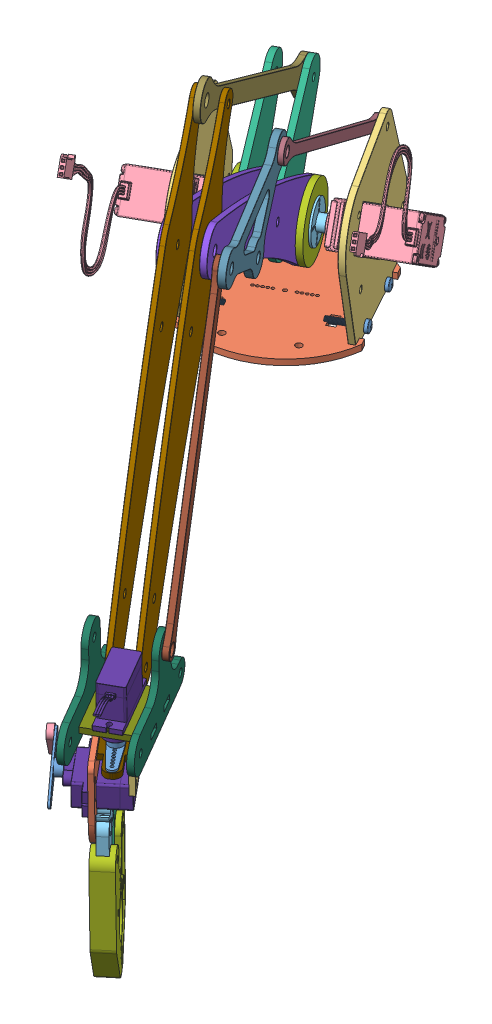
SolidWorks assembly Assem Arms2, configuration Default. Lengths in mm.
Overall size (226.25 313.58 319.53).
40 component instances, 25 part files, 102 mates.
Components (placement in the parent):
- pan head cross rece0ss screw_iso-20: pan head cross rece0ss screw_iso [ISO 7045 - M3 x 16 - Z - 16S] at (40.1963 16.3953 -44.7782) x (-0.87225 0 0.489061) z (-0.265849 -0.839351 -0.474146) size (18.35 5.6 5.6)
- pan head cross rece0ss screw_iso-22: pan head cross rece0ss screw_iso [ISO 7045 - M3 x 16 - Z - 16S] at (54.3761 16.9884 -19.4883) x (-0.87225 0 0.489061) z (0.426844 0.488109 0.761284) size (18.35 5.6 5.6)
- pan head cross rece0ss screw_iso-23: pan head cross rece0ss screw_iso [ISO 7045 - M3 x 16 - Z - 16S] at (-25.8377 16.3953 -7.7537) x (0.87225 0 -0.489061) z (0.489061 0 0.87225) size (18.35 5.6 5.6)
- pan head cross rece0ss screw_iso-24: pan head cross rece0ss screw_iso [ISO 7045 - M3 x 16 - Z - 16S] at (-11.6579 16.9884 17.5363) x (0.87225 0 -0.489061) z (0.489061 0 0.87225) size (18.35 5.6 5.6)
- Part9-1: Part9 [Default] at (14.258 13.6925 -13.5443) x (0.488959 0.020451 0.872067) z (-0.87225 0 0.489061) size (92 3 75)
- Part1-1: Part1 [Default] at (42.6761 6.6939 -29.314) x (-0.488959 -0.020451 -0.872067) z (0.87225 0 -0.489061) size (84.94 80.79 3)
- Part1-2: Part1 [Default] at (-16.5544 6.6939 3.8959) x (-0.488959 -0.020451 -0.872067) z (0.87225 0 -0.489061) size (84.94 80.79 3)
- Servo Futaba S3003.stp-1: Servo Futaba S3003.stp [Default] at (-33.8607 55.5272 21.081) x (-0.288648 0.80725 -0.51481) z (0.87225 0 -0.489061) size (44.37 151.18 42.35)
- Servo Futaba S3003.stp-2: Servo Futaba S3003.stp [Default] at (68.9822 55.5272 -36.5819) x (0.288648 -0.80725 0.51481) z (-0.87225 0 0.489061) size (44.37 151.18 42.35)
- SERVO MOTOR Leaf-2: SERVO MOTOR Leaf [Default] at (7.5067 61.4293 7.1415) x (-0.341934 -0.71496 -0.609846) z (-0.349659 0.699165 -0.623624) size (20 5 20)
- Part8-2: Part8 [Default] at (22.7419 116.7338 28.1796) x (-0.349659 0.699165 -0.623624) z (-0.87225 0 0.489061) size (80.5 35 3)
- Part8-3: Part8 [Default] at (35.4815 116.7338 21.0367) x (-0.349659 0.699165 -0.623624) z (-0.87225 0 0.489061) size (80.5 35 3)
- Waasher-3: Waasher [Default] at (10.1235 61.4293 5.6744) x (0.349659 -0.699165 0.623624) z (-0.87225 0 0.489061) size (35 35 3)
- Waasher-4: Waasher [Default] at (32.8939 61.4293 -7.0928) x (0.115909 -0.971509 0.206726) z (0.87225 0 -0.489061) size (35 35 3)
- Part2-3: Part2 [Default] at (6.2842 25.132 -48.4176) x (0.144187 -0.955551 0.257161) z (-0.87225 0 0.489061) size (60.81 172.93 3)
- Part2-4: Part2 [Default] at (-8.5441 25.132 -40.1035) x (0.144187 -0.955551 0.257161) z (-0.87225 0 0.489061) size (60.81 172.93 3)
- Part5-3: Part5 [Default] at (4.7495 30.3786 -51.1548) x (-0.343534 0.711748 -0.612699) z (0.87225 0 -0.489061) size (224.03 63.02 2.5)
- Part5-4: Part5 [Default] at (-5.2814 30.3786 -45.5306) x (-0.343534 0.711748 -0.612699) z (0.87225 0 -0.489061) size (224.03 63.02 2.5)
- SERVO MOTOR Leaf-3: SERVO MOTOR Leaf [Default] at (35.5107 61.4293 -8.56) x (-0.475127 -0.237003 -0.847398) z (0.115909 -0.971509 0.206726) size (20 5 20)
- Part22-1: Part22 [Default] at (7.5987 61.4293 7.09) x (-0.352996 -0.692118 -0.629576) z (0.338488 -0.721784 0.6037) size (8.5 32 8.5)
- part 6-2: part 6 [Default] at (11.9236 85.2607 -71.8932) x (-0.299121 0.79115 -0.533488) z (0.87225 0 -0.489061) size (153.11 32.4 3)
- Part4-2: Part4 [Default] at (-30.3251 112.5374 -90.1964) x (0.161206 -0.944113 0.287514) z (-0.87225 0 0.489061) size (50.31 174.7 3)
- Part 3-4: Part 3 [Default] at (-7.5406 76.9662 -113.7645) x (0.148401 -0.95285 0.264676) z (-0.87225 0 0.489061) size (42.48 154.39 2.5)
- Part7-2: Part7 [Default] at (122.5992 -71.5202 125.4988) x (0.48636 -0.104953 0.867432) z (-0.87225 0 0.489061) size (84.81 40.3 3.5)
- GPart 6-1: GPart 6 [Default] at (158.21 -6.5964 198.2127) x (0.488552 -0.045613 0.871342) z (-0.87225 0 0.489061) size (70 41 3)
- GPart 6-2: GPart 6 [Default] at (134.3104 -6.5964 211.613) x (0.488552 -0.045613 0.871342) z (-0.87225 0 0.489061) size (70 41 3)
- GPart 7-1: GPart 7 [Default] at (146.0278 -0.6255 205.9296) x (0.488552 -0.045613 0.871342) z (0.022308 0.998959 0.039786) size (31 29 3)
- SERVO MOTOR Leaf-4: SERVO MOTOR Leaf [Default] at (14.258 13.6925 -13.5443) x (0.489204 0.020451 0.87193) z (0.872112 -0.000006 -0.489306) size (20 5 20)
- Servo Motor-1: Servo Motor [Default] at (146.4851 19.8532 206.7452) x (0.488552 -0.045613 0.871342) z (0.87225 0 -0.489061) size (46.97 30.5 12)
- GPart 8-1: GPart 8 [Default] at (148.4136 -14.3623 210.1849) x (0.633536 -0.044911 0.772409) z (0.022308 0.998959 0.039786) size (35 18 3)
- SERVO MOTOR Leaf Straight-1: SERVO MOTOR Leaf Straight [Default] at (148.4471 -12.8639 210.2446) x (0.773392 0.007975 -0.633878) z (0.633536 -0.044911 0.772409) size (7.33 5 34.5)
- GPart 4-1: GPart 4 [Default] at (141.1343 -29.4196 215.3123) x (0.633536 -0.044911 0.772409) z (0.773392 0.007975 -0.633878) size (35 45 2.5)
- GPart 5-1: GPart 5 [Default] at (155.0554 -29.276 203.9025) x (-0.633536 0.044911 -0.772409) z (-0.773392 -0.007975 0.633878) size (35 13 2.5)
- Servo Motor-2: Servo Motor [Default] at (153.8953 -29.288 204.8533) x (-0.633536 0.044911 -0.772409) z (0.022308 0.998959 0.039786) size (46.97 30.5 12)
- SERVO MOTOR Leaf Straight-2: SERVO MOTOR Leaf Straight [Default] at (125.2756 -29.3002 221.2061) x (-0.296655 -0.879125 -0.373008) z (0.560233 -0.476524 0.677542) size (7.33 5 34.5)
- GPart 9-1: GPart 9 [Default] at (112.9469 -28.7956 208.5366) x (-0.36315 -0.814017 -0.45332) z (0.773392 0.007975 -0.633878) size (22.5 6.5 3)
- GPart 1-1: GPart 1 [Default] at (148.096 -45.7647 219.6565) x (0.773392 0.007975 -0.633878) z (0.633716 -0.035608 0.772746) size (5 59.63 16.16)
- GPart 2-1: GPart 2 [Default] at (137.3258 -45.0013 206.5256) x (0.773392 0.007975 -0.633878) z (0.633928 -0.011396 0.773308) size (5 63.64 32.05)
- GPart 3-1: GPart 3 [Default] at (144.4256 -59.8444 211.0572) x (-0.633716 0.035608 -0.772746) z (-0.773392 -0.007975 0.633878) size (17.75 66.5 10)
- GPart 3-2: GPart 3 [Default] at (144.6133 -59.4872 211.2907) x (0.633928 -0.011396 0.773308) z (0.773392 0.007975 -0.633878) size (17.75 66.5 10)
Mates (geometry in assembly coordinates):
- Coincident262: coincident anti-aligned: plane of Part9-1 through (31.33 16.2215 -49.5499) normal (0.87225 0 -0.489061); plane of Part1-1 through (51.9869 64.6754 -12.7079) normal (-0.87225 0 0.489061)
- Coincident263: coincident anti-aligned: plane of Part1-1 through (56.5389 7.1643 -10.7236) normal (0.488959 0.020451 0.872067); plane of Part9-1 through (58.1834 17.1622 -11.8801) normal (-0.488959 -0.020451 -0.872067)
- Coincident266: coincident anti-aligned: plane of Part9-1 through (-25.3486 16.2187 -17.9228) normal (-0.87225 0 0.489061); plane of Part1-2 through (-4.6268 64.6754 19.0348) normal (0.87225 0 -0.489061)
- Coincident267: coincident anti-aligned: plane of Part1-2 through (-2.6916 7.1643 22.4863) normal (0.488959 0.020451 0.872067); plane of Part9-1 through (-7.2353 17.1622 24.7995) normal (-0.488959 -0.020451 -0.872067)
- Coincident268: coincident anti-aligned: plane of Part1-1 through (54.6037 64.6754 -14.1751) normal (0.87225 0 -0.489061); plane of pan head cross rece0ss screw_iso-22 through (52.6408 15.6792 -17.6759) normal (-0.87225 0 0.489061)
- Concentric376: concentric aligned: cylinder of Part1-2 through (-9.5645 16.9884 16.3625) axis (-0.87225 0 0.489061) radius 1.6; circle of pan head cross recess screw_iso-24
- Concentric377: concentric aligned: cylinder of Part1-2 through (-23.7443 16.3953 -8.9274) axis (-0.87225 0 0.489061) radius 1.6; circle of pan head cross recess screw_iso-23
- Concentric378: concentric anti-aligned: cylinder of Part1-1 through (35.4862 16.3953 -42.1373) axis (-0.87225 0 0.489061) radius 1.6; circle of pan head cross recess screw_iso-20
- Concentric379: concentric anti-aligned: cylinder of Part1-1 through (49.666 16.9884 -16.8474) axis (-0.87225 0 0.489061) radius 1.6; circle of pan head cross recess screw_iso-22
- Coincident269: coincident anti-aligned: plane of Part1-1 through (54.6037 64.6754 -14.1751) normal (0.87225 0 -0.489061); plane of pan head cross rece0ss screw_iso-20 through (37.4872 17.2107 -44.7027) normal (-0.87225 0 0.489061)
- Coincident271: coincident anti-aligned: plane of Part9-1 through (14.228 16.6918 -13.5979) normal (-0.010002 0.999791 -0.017839); plane of Part1-1 through (33.9468 16.2215 -51.0171) normal (0.010002 -0.999791 0.017839)
- Coincident272: coincident anti-aligned: plane of Part9-1 through (14.228 16.6918 -13.5979) normal (-0.010002 0.999791 -0.017839); plane of Part1-2 through (-25.2837 16.2215 -17.8072) normal (0.010002 -0.999791 0.017839)
- Coincident273: coincident anti-aligned: plane of Part1-2 through (-7.2436 64.6754 20.502) normal (-0.87225 0 0.489061); plane of pan head cross rece0ss screw_iso-23 through (-23.7443 17.8953 -8.9274) normal (0.87225 0 -0.489061)
- Coincident274: coincident anti-aligned: plane of Part1-2 through (-7.2436 64.6754 20.502) normal (-0.87225 0 0.489061); plane of pan head cross rece0ss screw_iso-24 through (-9.5645 18.4884 16.3625) normal (0.87225 0 -0.489061)
- Coincident3367: coincident anti-aligned: plane of Part1-1 through (51.9869 64.6754 -12.7079) normal (-0.87225 0 0.489061); plane of Servo Futaba S3003.stp-2 through (56.8034 71.876 -4.1176) normal (0.87225 0 -0.489061)
- Concentric4730: concentric anti-aligned: cylinder of Part1-1 through (59.6001 65.951 -5.2639) axis (-0.87225 0 0.489061) radius 1.55; cylinder of Servo Futaba S3003.stp-2 through (55.1952 65.951 -2.7942) axis (0.87225 0 -0.489061) radius 1.35
- Concentric4731: concentric anti-aligned: cylinder of Part1-1 through (37.3687 45.1033 -44.9141) axis (-0.87225 0 0.489061) radius 1.55; cylinder of Servo Futaba S3003.stp-2 through (32.9638 45.1033 -42.4443) axis (0.87225 0 -0.489061) radius 1.35
- Coincident3368: coincident anti-aligned: plane of Part1-2 through (-4.6268 64.6754 19.0348) normal (0.87225 0 -0.489061); plane of Servo Futaba S3003.stp-1 through (0.1897 71.876 27.6251) normal (-0.87225 0 0.489061)
- Concentric4732: concentric aligned: cylinder of Part1-2 through (-2.5169 74.0235 22.7979) axis (-0.87225 0 0.489061) radius 1.55; cylinder of Servo Futaba S3003.stp-1 through (-0.7288 74.0235 21.7953) axis (-0.87225 0 0.489061) radius 1.35
- Concentric4733: concentric aligned: cylinder of Part1-2 through (-18.9753 37.0308 -6.5561) axis (-0.87225 0 0.489061) radius 1.55; cylinder of Servo Futaba S3003.stp-1 through (-17.1872 37.0308 -7.5587) axis (-0.87225 0 0.489061) radius 1.35
- Concentric4736: concentric aligned: cylinder of Servo Futaba S3003.stp-1 through (4.9772 61.4293 8.5598) axis (0.87225 0 -0.489061) radius 3; cylinder of SERVO MOTOR Leaf-2 through (3.1455 61.4293 9.5868) axis (0.87225 0 -0.489061) radius 2.5
- Coincident3370: coincident anti-aligned: plane of Servo Futaba S3003.stp-1 through (-0.8025 55.5272 2.5456) normal (0.87225 0 -0.489061); plane of SERVO MOTOR Leaf-2 through (3.1455 61.4293 9.5868) normal (-0.87225 0 0.489061)
- Coincident3371: coincident anti-aligned: plane of Waasher-4 through (32.8939 61.4293 -7.0928) normal (-0.87225 0 0.489061); plane of Part2-3 through (146.5206 -98.554 195.5626) normal (0.87225 0 -0.489061)
- Concentric4739: concentric anti-aligned: cylinder of Waasher-4 through (34.7283 67.9869 -9.9554) axis (-0.87225 0 0.489061) radius 0.8; cylinder of Part2-3 through (23.389 67.9869 -3.5976) axis (0.87225 0 -0.489061) radius 0.8
- Concentric4740: concentric aligned: cylinder of Waasher-4 through (35.5107 61.4293 -8.56) axis (-0.87225 0 0.489061) radius 4.25; cylinder of Part2-3 through (32.8939 61.4293 -7.0928) axis (-0.87225 0 0.489061) radius 4.25
- Concentric4741: concentric aligned: cylinder of Waasher-4 through (35.5107 61.4293 -8.56) axis (-0.87225 0 0.489061) radius 4.25; cylinder of SERVO MOTOR Leaf-3 through (36.3829 61.4293 -9.049) axis (-0.87225 0 0.489061) radius 0.75
- Concentric4742: concentric anti-aligned: cylinder of Waasher-4 through (39.668 63.503 -1.1452) axis (-0.87225 0 0.489061) radius 0.8; circle of SERVO MOTOR Leaf-3
- Coincident3372: coincident anti-aligned: plane of Waasher-4 through (35.5107 61.4293 -8.56) normal (0.87225 0 -0.489061); plane of SERVO MOTOR Leaf-3 through (33.801 75.759 -11.6092) normal (-0.87225 0 0.489061)
- Concentric4743: concentric aligned: cylinder of Servo Futaba S3003.stp-2 through (38.0402 61.4293 -9.9783) axis (-0.87225 0 0.489061) radius 3; cylinder of SERVO MOTOR Leaf-3 through (39.8719 61.4293 -11.0053) axis (-0.87225 0 0.489061) radius 2.5
- Coincident3373: coincident anti-aligned: plane of Servo Futaba S3003.stp-2 through (35.924 55.5272 -18.0465) normal (-0.87225 0 0.489061); plane of SERVO MOTOR Leaf-3 through (39.8719 61.4293 -11.0053) normal (0.87225 0 -0.489061)
- Coincident3377: coincident anti-aligned: plane of SERVO MOTOR Leaf-2 through (12.6642 51.1166 16.34) normal (0.87225 0 -0.489061); plane of Waasher-3 through (7.5067 61.4293 7.1415) normal (-0.87225 0 0.489061)
- Concentric4750: concentric aligned: cylinder of SERVO MOTOR Leaf-2 through (9.6264 67.6852 12.9667) axis (0.87225 0 -0.489061) radius 0.75; cylinder of Waasher-3 through (10.4986 67.6852 12.4777) axis (0.87225 0 -0.489061) radius 0.8
- Concentric4751: concentric aligned: cylinder of SERVO MOTOR Leaf-2 through (4.2743 66.1486 3.4211) axis (0.87225 0 -0.489061) radius 0.75; cylinder of Waasher-3 through (5.1465 66.1486 2.9321) axis (0.87225 0 -0.489061) radius 0.8
- Concentric4752: concentric aligned: cylinder of Part2-3 through (32.8939 61.4293 -7.0928) axis (-0.87225 0 0.489061) radius 4.25; cylinder of Part22-1 through (35.5107 61.4293 -8.56) axis (-0.87225 0 0.489061) radius 4.25
- Coincident3378: coincident anti-aligned: plane of SERVO MOTOR Leaf-3 through (33.801 75.759 -11.6092) normal (-0.87225 0 0.489061); plane of Part22-1 through (35.5107 61.4293 -8.56) normal (0.87225 0 -0.489061)
- Concentric4754: concentric aligned: cylinder of Part8-3 through (25.4798 61.4293 -2.9358) axis (-0.87225 0 0.489061) radius 4.25; cylinder of Part22-1 through (35.5107 61.4293 -8.56) axis (-0.87225 0 0.489061) radius 4.25
- Distance1: distance = 5.5 mm anti-aligned: plane of Part2-3 through (143.9039 -98.554 197.0298) normal (-0.87225 0 0.489061); plane of Part8-3 through (25.4798 61.4293 -2.9358) normal (0.87225 0 -0.489061)
- Concentric4755: concentric aligned: cylinder of Part2-4 through (18.0657 61.4293 1.2212) axis (-0.87225 0 0.489061) radius 4.25; cylinder of Part22-1 through (35.5107 61.4293 -8.56) axis (-0.87225 0 0.489061) radius 4.25
- Distance2: distance = 14 mm anti-aligned: plane of Part2-3 through (143.9039 -98.554 197.0298) normal (-0.87225 0 0.489061); plane of Part2-4 through (131.6924 -98.554 203.8766) normal (0.87225 0 -0.489061)
- Concentric4756: concentric aligned: cylinder of Part8-2 through (12.7402 61.4293 4.2072) axis (-0.87225 0 0.489061) radius 4.25; cylinder of Part22-1 through (35.5107 61.4293 -8.56) axis (-0.87225 0 0.489061) radius 4.25
- Concentric4757: concentric anti-aligned: cylinder of Part8-2 through (15.7321 67.6852 9.5433) axis (-0.87225 0 0.489061) radius 0.8; cylinder of Waasher-3 through (10.4986 67.6852 12.4777) axis (0.87225 0 -0.489061) radius 0.8
- Concentric4758: concentric anti-aligned: cylinder of Part8-2 through (15.1004 56.7099 8.4166) axis (-0.87225 0 0.489061) radius 0.8; cylinder of Waasher-3 through (9.8669 56.7099 11.351) axis (0.87225 0 -0.489061) radius 0.8
- Coincident3381: coincident anti-aligned: plane of Part8-2 through (10.1235 61.4293 5.6744) normal (-0.87225 0 0.489061); plane of Waasher-3 through (10.1235 61.4293 5.6744) normal (0.87225 0 -0.489061)
- Concentric4759: concentric aligned: cylinder of Part8-2 through (-5.9956 99.4866 -29.2085) axis (-0.87225 0 0.489061) radius 1.75; cylinder of Part8-3 through (6.744 99.4866 -36.3515) axis (-0.87225 0 0.489061) radius 1.75
- Concentric4760: concentric aligned: cylinder of Part8-3 through (6.744 99.4866 -36.3515) axis (-0.87225 0 0.489061) radius 1.75; cylinder of Part4-2 through (15.5992 99.4866 -41.3165) axis (-0.87225 0 0.489061) radius 3
- Coincident3382: coincident anti-aligned: plane of Part8-3 through (22.8631 61.4293 -1.4686) normal (-0.87225 0 0.489061); plane of Part4-2 through (-27.7083 112.5374 -91.6636) normal (0.87225 0 -0.489061)
- Concentric4761: concentric aligned: cylinder of Part1-1 through (34.771 87.8803 -43.4128) axis (-0.87225 0 0.489061) radius 1.6; cylinder of Part 3-4 through (34.771 87.8803 -43.4128) axis (-0.87225 0 0.489061) radius 2.5
- Coincident3383: coincident anti-aligned: plane of Part1-1 through (51.9869 64.6754 -12.7079) normal (-0.87225 0 0.489061); plane of Part 3-4 through (-5.3599 76.9662 -114.9871) normal (0.87225 0 -0.489061)
- Concentric4762: concentric anti-aligned: cylinder of Part2-4 through (80.9018 134.8871 113.2907) axis (-0.87225 0 0.489061) radius 2.5; cylinder of Part5-4 through (83.0824 134.8871 112.068) axis (0.87225 0 -0.489061) radius 1.85
- Coincident3384: coincident anti-aligned: plane of Part2-4 through (131.6924 -98.554 203.8766) normal (0.87225 0 -0.489061); plane of Part5-4 through (-57.8276 -220.2316 -134.1358) normal (-0.87225 0 0.489061)
- Concentric4763: concentric anti-aligned: cylinder of Part2-3 through (95.7301 134.8871 104.9767) axis (-0.87225 0 0.489061) radius 2.5; cylinder of Part5-3 through (93.1133 134.8871 106.4438) axis (0.87225 0 -0.489061) radius 1.85
- Coincident3385: coincident anti-aligned: plane of Part2-3 through (143.9039 -98.554 197.0298) normal (-0.87225 0 0.489061); plane of Part5-3 through (-45.6161 -220.2316 -140.9827) normal (0.87225 0 -0.489061)
- Concentric4764: concentric anti-aligned: cylinder of Part5-4 through (68.6563 181.6449 86.3387) axis (0.87225 0 -0.489061) radius 1.85; cylinder of Part4-2 through (82.745 181.6449 78.4393) axis (-0.87225 0 0.489061) radius 3
- Concentric4765: concentric anti-aligned: cylinder of Part5-3 through (78.6871 181.6449 80.7145) axis (0.87225 0 -0.489061) radius 1.85; cylinder of Part4-2 through (82.745 181.6449 78.4393) axis (-0.87225 0 0.489061) radius 3
- Concentric4766: concentric aligned: cylinder of Part 3-4 through (97.2371 162.6462 67.9966) axis (-0.87225 0 0.489061) radius 2.5; cylinder of Part7-2 through (95.0565 162.6462 69.2193) axis (-0.87225 0 0.489061) radius 2.5
- Coincident3387: coincident anti-aligned: plane of Part 3-4 through (-7.5406 76.9662 -113.7645) normal (-0.87225 0 0.489061); plane of Part7-2 through (95.0565 162.6462 69.2193) normal (0.87225 0 -0.489061)
- Concentric4767: concentric aligned: cylinder of Part2-3 through (95.7301 134.8871 104.9767) axis (-0.87225 0 0.489061) radius 2.5; cylinder of Part7-2 through (110.4711 134.8871 96.7115) axis (-0.87225 0 0.489061) radius 2.5
- Concentric4768: concentric anti-aligned: cylinder of part 6-2 through (122.8307 155.0109 132.046) axis (0.87225 0 -0.489061) radius 3; cylinder of Part7-2 through (128.5003 155.0109 128.8671) axis (-0.87225 0 0.489061) radius 2.5
- Coincident3388: coincident anti-aligned: plane of part 6-2 through (11.9236 85.2607 -71.8932) normal (0.87225 0 -0.489061); plane of Part7-2 through (92.0036 162.6462 70.931) normal (-0.87225 0 0.489061)
- Concentric4769: concentric aligned: cylinder of part 6-2 through (156.8836 26.684 192.7798) axis (0.87225 0 -0.489061) radius 3; cylinder of GPart 6-1 through (154.2668 26.684 194.247) axis (0.87225 0 -0.489061) radius 2
- Coincident3389: coincident anti-aligned: plane of part 6-2 through (9.3069 85.2607 -70.426) normal (-0.87225 0 0.489061); plane of GPart 6-1 through (146.2171 0.6517 173.756) normal (0.87225 0 -0.489061)
- Concentric4770: concentric aligned: cylinder of Part5-3 through (134.5289 0.6517 180.3094) axis (0.87225 0 -0.489061) radius 1.85; cylinder of GPart 6-1 through (143.6003 0.6517 175.2232) axis (0.87225 0 -0.489061) radius 2
- Concentric4771: concentric aligned: cylinder of Part5-4 through (124.4981 0.6517 185.9336) axis (0.87225 0 -0.489061) radius 1.85; cylinder of GPart 6-2 through (119.7007 0.6517 188.6234) axis (0.87225 0 -0.489061) radius 2
- Coincident3390: coincident anti-aligned: plane of Part5-4 through (-57.8276 -220.2316 -134.1358) normal (-0.87225 0 0.489061); plane of GPart 6-2 through (122.3174 0.6517 187.1562) normal (0.87225 0 -0.489061)
- Concentric4772: concentric aligned: cylinder of GPart 6-1 through (170.5376 1.1398 223.2663) axis (0.87225 0 -0.489061) radius 1.85; cylinder of GPart 6-2 through (146.638 1.1398 236.6666) axis (0.87225 0 -0.489061) radius 1.85
- Coincident3391: coincident aligned: plane of GPart 6-2 through (119.7007 0.6517 188.6234) normal (-0.87225 0 0.489061); plane of GPart 7-1 through (133.4136 0.873 213.0807) normal (-0.87225 0 0.489061)
- Coincident3392: coincident anti-aligned: plane of GPart 6-2 through (139.7648 0.28 224.4081) normal (-0.488552 0.045613 -0.871342); plane of GPart 7-1 through (152.4124 0.28 217.3167) normal (0.488552 -0.045613 0.871342)
- Coincident3393: coincident anti-aligned: plane of GPart 6-2 through (135.7894 -2.352 217.318) normal (0.022308 0.998959 0.039786); plane of GPart 7-1 through (145.9943 -2.1239 205.8699) normal (-0.022308 -0.998959 -0.039786)
- Concentric4773: concentric anti-aligned: cylinder of Part9-1 through (14.228 16.6918 -13.5979) axis (0.010002 -0.999791 0.017839) radius 1; cylinder of SERVO MOTOR Leaf-4 through (14.268 12.6927 -13.5265) axis (-0.010002 0.999791 -0.017839) radius 0.75
- Coincident3394: coincident anti-aligned: plane of Part9-1 through (14.258 13.6925 -13.5443) normal (0.010002 -0.999791 0.017839); plane of SERVO MOTOR Leaf-4 through (1.3943 13.6925 -6.3271) normal (-0.010002 0.999791 -0.017839)
- Coincident3396: coincident anti-aligned: plane of GPart 7-1 through (146.0612 0.873 205.9893) normal (0.022308 0.998959 0.039786); plane of Servo Motor-1 through (152.901 0.2344 218.1881) normal (-0.022308 -0.998959 -0.039786)
- Concentric4775: concentric anti-aligned: cylinder of GPart 7-1 through (152.901 0.2344 218.1881) axis (-0.022308 -0.998959 -0.039786) radius 1; cylinder of Servo Motor-1 through (152.901 0.2344 218.1881) axis (0.022308 0.998959 0.039786) radius 1.25
- Concentric4776: concentric anti-aligned: cylinder of GPart 7-1 through (139.2215 1.5115 193.7905) axis (-0.022308 -0.998959 -0.039786) radius 1; cylinder of Servo Motor-1 through (139.2215 1.5115 193.7905) axis (0.022308 0.998959 0.039786) radius 1.25
- Concentric4777: concentric aligned: cylinder of Servo Motor-1 through (148.5029 -10.3665 210.344) axis (0.022308 0.998959 0.039786) radius 2.5; cylinder of SERVO MOTOR Leaf Straight-1 through (148.514 -9.867 210.3639) axis (0.022308 0.998959 0.039786) radius 2.355
- Coincident3397: coincident anti-aligned: plane of Servo Motor-1 through (147.0319 -7.7265 207.7205) normal (-0.022308 -0.998959 -0.039786); plane of SERVO MOTOR Leaf Straight-1 through (148.5586 -7.8691 210.4435) normal (0.022308 0.998959 0.039786)
- Concentric4778: concentric aligned: cylinder of GPart 8-1 through (148.4471 -12.8639 210.2446) axis (-0.022308 -0.998959 -0.039786) radius 0.75; cylinder of SERVO MOTOR Leaf Straight-1 through (148.4583 -12.3644 210.2645) axis (-0.022308 -0.998959 -0.039786) radius 1.5
- Concentric4779: concentric anti-aligned: cylinder of GPart 8-1 through (151.3895 -16.0741 213.7941) axis (0.022308 0.998959 0.039786) radius 0.75; cylinder of SERVO MOTOR Leaf Straight-1 through (151.4787 -12.0782 213.9533) axis (-0.022308 -0.998959 -0.039786) radius 0.75
- Coincident3398: coincident anti-aligned: plane of GPart 8-1 through (139.1909 -12.2391 199.7478) normal (0.022308 0.998959 0.039786); plane of SERVO MOTOR Leaf Straight-1 through (139.1025 -12.2014 198.8515) normal (-0.022308 -0.998959 -0.039786)
- Coincident3399: coincident anti-aligned: plane of GPart 8-1 through (139.124 -15.236 199.6284) normal (-0.022308 -0.998959 -0.039786); plane of GPart 5-1 through (157.351 -16.0885 210.8132) normal (0.022308 0.998959 0.039786)
- Coincident3400: coincident aligned: plane of GPart 8-1 through (151.4956 -12.5148 199.77) normal (0.773392 0.007975 -0.633878); plane of GPart 5-1 through (154.8659 -37.7598 203.5646) normal (0.773392 0.007975 -0.633878)
- Distance3: distance = 0 mm: cylinder of GPart 5-1 through (149.5286 -14.0331 201.295) axis (0.773392 0.007975 -0.633878) radius 1.5; plane of GPart 8-1 through (147.6286 -12.5546 202.9394) normal (-0.633536 0.044911 -0.772409)
- Coincident3403: coincident anti-aligned: plane of GPart 8-1 through (139.124 -15.236 199.6284) normal (-0.022308 -0.998959 -0.039786); plane of GPart 4-1 through (139.4411 -15.6353 209.4758) normal (0.022308 0.998959 0.039786)
- Coincident3404: coincident aligned: plane of GPart 8-1 through (145.3987 -13.213 220.7191) normal (-0.773392 -0.007975 0.633878); plane of GPart 4-1 through (140.9449 -37.9034 214.9744) normal (-0.773392 -0.007975 0.633878)
- Coincident3405: coincident aligned: plane of GPart 4-1 through (131.7802 -37.6043 199.8524) normal (-0.633536 0.044911 -0.772409); plane of GPart 5-1 through (141.8343 -37.5007 191.612) normal (-0.633536 0.044911 -0.772409)
- Coincident3407: coincident anti-aligned: plane of GPart 4-1 through (140.9449 -37.9034 214.9744) normal (-0.773392 -0.007975 0.633878); plane of Servo Motor-2 through (141.1343 -29.4196 215.3123) normal (0.773392 0.007975 -0.633878)
- Concentric4780: concentric anti-aligned: cylinder of GPart 4-1 through (134.1983 -28.7709 202.9139) axis (-0.773392 -0.007975 0.633878) radius 1; cylinder of Servo Motor-2 through (130.3314 -28.8108 206.0833) axis (0.773392 0.007975 -0.633878) radius 1.25
- Concentric4781: concentric anti-aligned: cylinder of GPart 4-1 through (151.9373 -30.0284 224.5413) axis (-0.773392 -0.007975 0.633878) radius 1; cylinder of Servo Motor-2 through (148.0704 -30.0683 227.7107) axis (0.773392 0.007975 -0.633878) radius 1.25
- Concentric4782: concentric aligned: cylinder of Servo Motor-2 through (127.2091 -29.2802 219.6214) axis (0.773392 0.007975 -0.633878) radius 2.5; cylinder of SERVO MOTOR Leaf Straight-2 through (127.5958 -29.2763 219.3045) axis (0.773392 0.007975 -0.633878) radius 2.355
- Coincident3408: coincident anti-aligned: plane of Servo Motor-2 through (131.1224 -29.4007 220.4505) normal (-0.773392 -0.007975 0.633878); plane of SERVO MOTOR Leaf Straight-2 through (129.1426 -29.2603 218.0367) normal (0.773392 0.007975 -0.633878)
- Concentric4783: concentric aligned: cylinder of SERVO MOTOR Leaf Straight-2 through (117.7856 -22.2635 210.5785) axis (-0.773392 -0.007975 0.633878) radius 0.75; cylinder of GPart 9-1 through (117.0122 -22.2715 211.2124) axis (-0.773392 -0.007975 0.633878) radius 0.75
- Coincident3409: coincident anti-aligned: plane of SERVO MOTOR Leaf Straight-2 through (117.0122 -22.2715 211.2124) normal (-0.773392 -0.007975 0.633878); plane of GPart 9-1 through (117.0122 -22.2715 211.2124) normal (0.773392 0.007975 -0.633878)
- Concentric4784: concentric anti-aligned: cylinder of GPart 4-1 through (137.3258 -45.0013 206.5256) axis (-0.773392 -0.007975 0.633878) radius 2; cylinder of GPart 2-1 through (133.4589 -45.0411 209.6949) axis (0.773392 0.007975 -0.633878) radius 3.5
- Coincident3410: coincident anti-aligned: plane of GPart 4-1 through (142.8784 -37.8835 213.3897) normal (0.773392 0.007975 -0.633878); plane of GPart 2-1 through (137.3258 -45.0013 206.5256) normal (-0.773392 -0.007975 0.633878)
- Concentric4785: concentric anti-aligned: cylinder of GPart 9-1 through (111.2018 -35.2957 203.9592) axis (-0.773392 -0.007975 0.633878) radius 1.5; cylinder of GPart 2-1 through (104.7214 -35.3625 209.2706) axis (0.773392 0.007975 -0.633878) radius 1.5
- Concentric4786: concentric anti-aligned: cylinder of GPart 4-1 through (148.096 -45.7647 219.6565) axis (-0.773392 -0.007975 0.633878) radius 2; cylinder of GPart 1-1 through (144.229 -45.8046 222.8259) axis (0.773392 0.007975 -0.633878) radius 3.5
- Coincident3411: coincident anti-aligned: plane of GPart 4-1 through (142.8784 -37.8835 213.3897) normal (0.773392 0.007975 -0.633878); plane of GPart 1-1 through (148.096 -45.7647 219.6565) normal (-0.773392 -0.007975 0.633878)
- Concentric4787: concentric aligned: cylinder of GPart 2-1 through (140.366 -59.3562 202.1663) axis (-0.773392 -0.007975 0.633878) radius 1.5; cylinder of GPart 3-2 through (142.2995 -59.3363 200.5816) axis (-0.773392 -0.007975 0.633878) radius 1.5
- Coincident3413: coincident anti-aligned: plane of GPart 2-1 through (137.3258 -45.0013 206.5256) normal (-0.773392 -0.007975 0.633878); plane of GPart 3-2 through (140.7848 -53.0628 210.6444) normal (0.773392 0.007975 -0.633878)
- Concentric4788: concentric aligned: cylinder of GPart 2-1 through (140.3396 -84.3538 201.8195) axis (-0.773392 -0.007975 0.633878) radius 1.5; cylinder of GPart 3-2 through (142.2731 -84.3338 200.2348) axis (-0.773392 -0.007975 0.633878) radius 1.5
- Concentric4789: concentric anti-aligned: cylinder of GPart 1-1 through (152.5378 -60.1716 217.0067) axis (-0.773392 -0.007975 0.633878) radius 1.5; cylinder of GPart 3-1 through (146.7373 -60.2315 221.7608) axis (0.773392 0.007975 -0.633878) radius 1.5
- Coincident3414: coincident anti-aligned: plane of GPart 1-1 through (148.096 -45.7647 219.6565) normal (-0.773392 -0.007975 0.633878); plane of GPart 3-1 through (144.4984 -53.5646 215.169) normal (0.773392 0.007975 -0.633878)
- Concentric4790: concentric anti-aligned: cylinder of GPart 1-1 through (152.1276 -85.155 216.1919) axis (-0.773392 -0.007975 0.633878) radius 1.5; cylinder of GPart 3-1 through (146.3271 -85.2148 220.946) axis (0.773392 0.007975 -0.633878) radius 1.5
